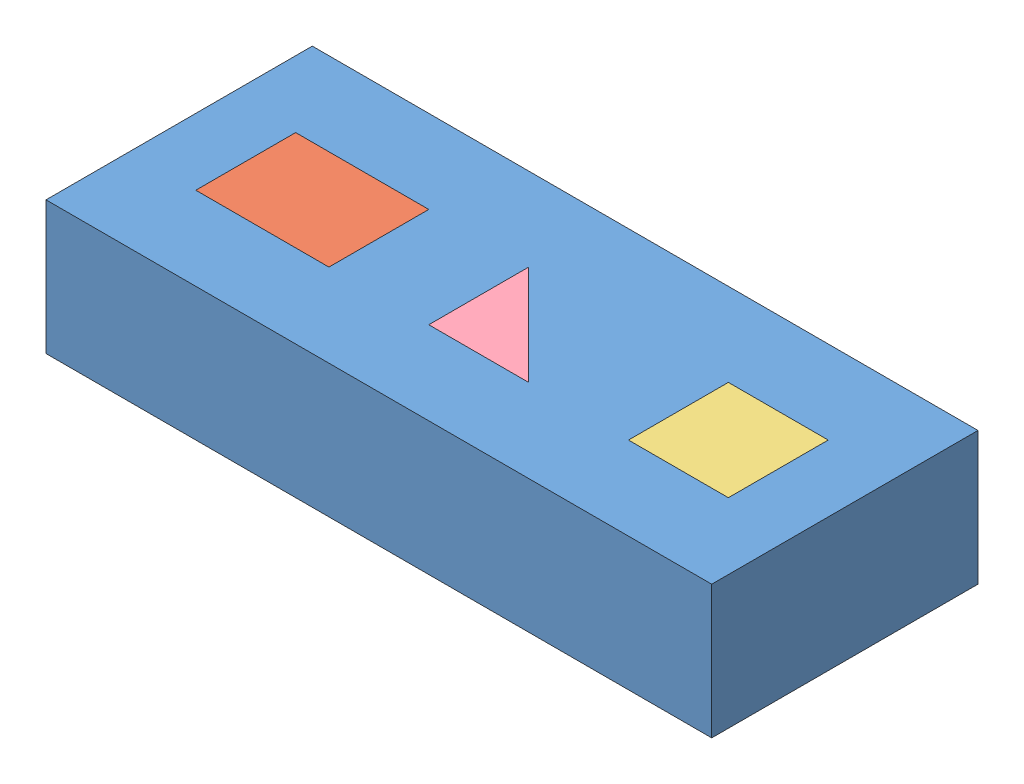
SolidWorks assembly Assembly 59, configuration Default. Lengths in mm.
Overall size (127 25.4 50.8).
4 component instances, 4 part files, 10 mates.
Components (placement in the parent):
- Block_Coinc_parallel_prepend_2013-1: Block_Coinc_parallel_prepend_2013 [Default] at (-15.1736 49.2506 125.3358) size (127 25.4 50.8)
- rectangle_1_2013-1: rectangle_1_2013 [Default] at (-2.4736 49.2506 109.4608) size (25.4 25.4 19.05)
- Square_2013-1: Square_2013 [Default] at (80.0764 49.2506 109.4608) size (19.05 25.4 19.05)
- Traingle_2013-1: Traingle_2013 [Default] at (41.9764 49.2506 109.4608) size (19.05 25.4 19.05)
Mates (geometry in assembly coordinates):
- Coincident1: coincident: point of Block_Coinc_parallel_prepend_2013-1; point of rectangle_1_2013-1
- Coincident2: coincident: point of Block_Coinc_parallel_prepend_2013-1; point of rectangle_1_2013-1
- Coincident3: coincident aligned: plane of Block_Coinc_parallel_prepend_2013-1 through (-15.1736 74.6506 125.3358) normal (0 1 0); plane of rectangle_1_2013-1 through (-2.4736 74.6506 109.4608) normal (0 1 0)
- Perpendicular1: perpendicular: plane of Block_Coinc_parallel_prepend_2013-1 through (41.9764 49.2506 90.4108) normal (1 0 0); plane of Traingle_2013-1 through (41.9764 74.6506 109.4608) normal (0 0 1)
- Coincident5: coincident: line of Block_Coinc_parallel_prepend_2013-1 through (61.0264 49.2506 109.4608) axis (0 1 0); line of Traingle_2013-1 through (61.0264 74.6506 109.4608) axis (0 -1 0)
- Coincident6: coincident aligned: plane of Block_Coinc_parallel_prepend_2013-1 through (-15.1736 74.6506 125.3358) normal (0 1 0); plane of Traingle_2013-1 through (41.9764 74.6506 109.4608) normal (0 1 0)
- Parallel1: parallel: plane of Block_Coinc_parallel_prepend_2013-1 through (80.0764 49.2506 109.4608) normal (0 0 -1); plane of Square_2013-1 through (80.0764 74.6506 109.4608) normal (0 0 1)
- Coincident8: coincident: plane of Block_Coinc_parallel_prepend_2013-1 through (-15.1736 74.6506 125.3358) normal (0 1 0); plane of Square_2013-1 through (80.0764 74.6506 109.4608) normal (0 1 0)
- Coincident9: coincident: plane of Block_Coinc_parallel_prepend_2013-1 through (99.1264 49.2506 109.4608) normal (-1 0 0); plane of Square_2013-1 through (99.1264 74.6506 109.4608) normal (1 0 0)
- Coincident10: coincident anti-aligned: plane of Block_Coinc_parallel_prepend_2013-1 through (80.0764 49.2506 109.4608) normal (0 0 -1); plane of Square_2013-1 through (80.0764 74.6506 109.4608) normal (0 0 1)
